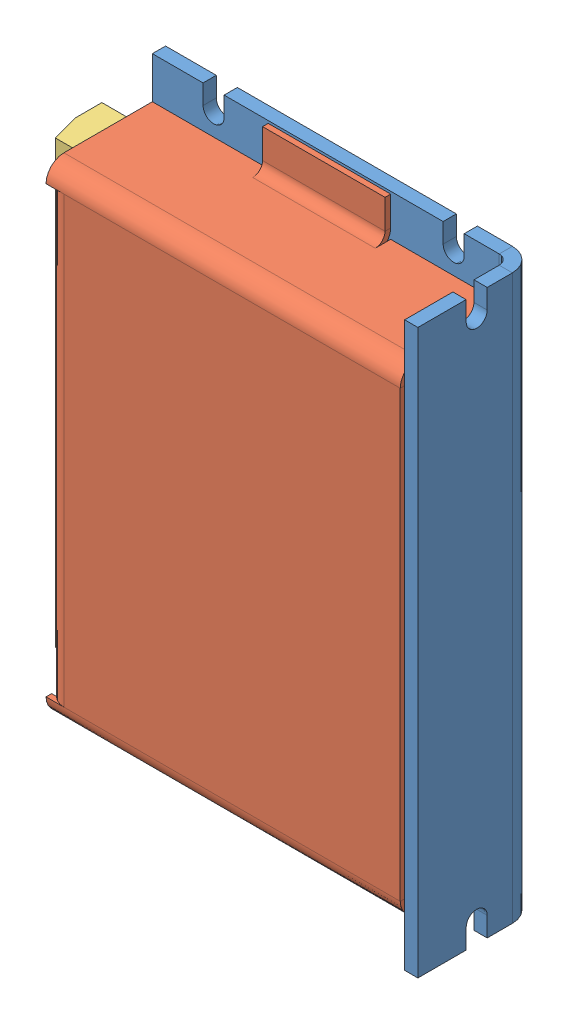
SolidWorks assembly ESCON, configuration Default. Lengths in mm.
Overall size (84.5 115 24.4).
3 component instances, 3 part files, 7 mates.
Components (placement in the parent):
- Baseplate^ESCON-1: Baseplate^ESCON [Default] at origin size (75.5 115 24) (virtual)
- Cover^ESCON-1: Cover^ESCON [Default] at (36.15 57.5 21.7) x (1 0 0) z (0 -1 0) size (72.3 21.7 114) (virtual)
- Terminals^ESCON-1: Terminals^ESCON [Default] at (-4.5 102.5 6.8) x (0 -1 0) z (-1 0 0) size (90 11 9) (virtual)
Mates (geometry in assembly coordinates):
- Coincident1: coincident anti-aligned: plane of Baseplate^ESCON-1 through (0 0 0) normal (0 0 1); plane of Cover^ESCON-1 through (36.15 57.5 0) normal (0 0 -1)
- Coincident2: coincident aligned: plane of Baseplate^ESCON-1 through (0 0 -2.7) normal (-1 0 0); plane of Cover^ESCON-1 through (0 8.5 0) normal (-1 0 0)
- Coincident5: coincident: point of Baseplate^ESCON-1; plane of Cover^ESCON-1 through (36.15 57.5 21.7) normal (0 -1 0)
- Coincident6: coincident anti-aligned: plane of Baseplate^ESCON-1 through (0 0 -2.7) normal (-1 0 0); plane of Terminals^ESCON-1 through (0 12.5 1.3) normal (1 0 0)
- Parallel1: parallel anti-aligned: plane of Cover^ESCON-1 through (36.15 9.65 21.7) normal (0 1 0); plane of Part5^ESCON-1 through (-4.5 12.5 6.8) normal (0 -1 0)
- Symmetric1: symmetric aligned: plane of Baseplate^ESCON-1 through (0 57.5 0) normal (0 -1 0); plane of Terminals^ESCON-1 through (-4.5 12.5 6.8) normal (0 -1 0); plane of Terminals^ESCON-1 through (-4.5 102.5 6.8) normal (0 1 0)
- Distance1: distance = 4 mm aligned: plane of Part5^ESCON-1 through (-9 12.5 1.3) normal (0 0 -1); plane of Baseplate^ESCON-1 through (0 0 -2.7) normal (0 0 -1)
